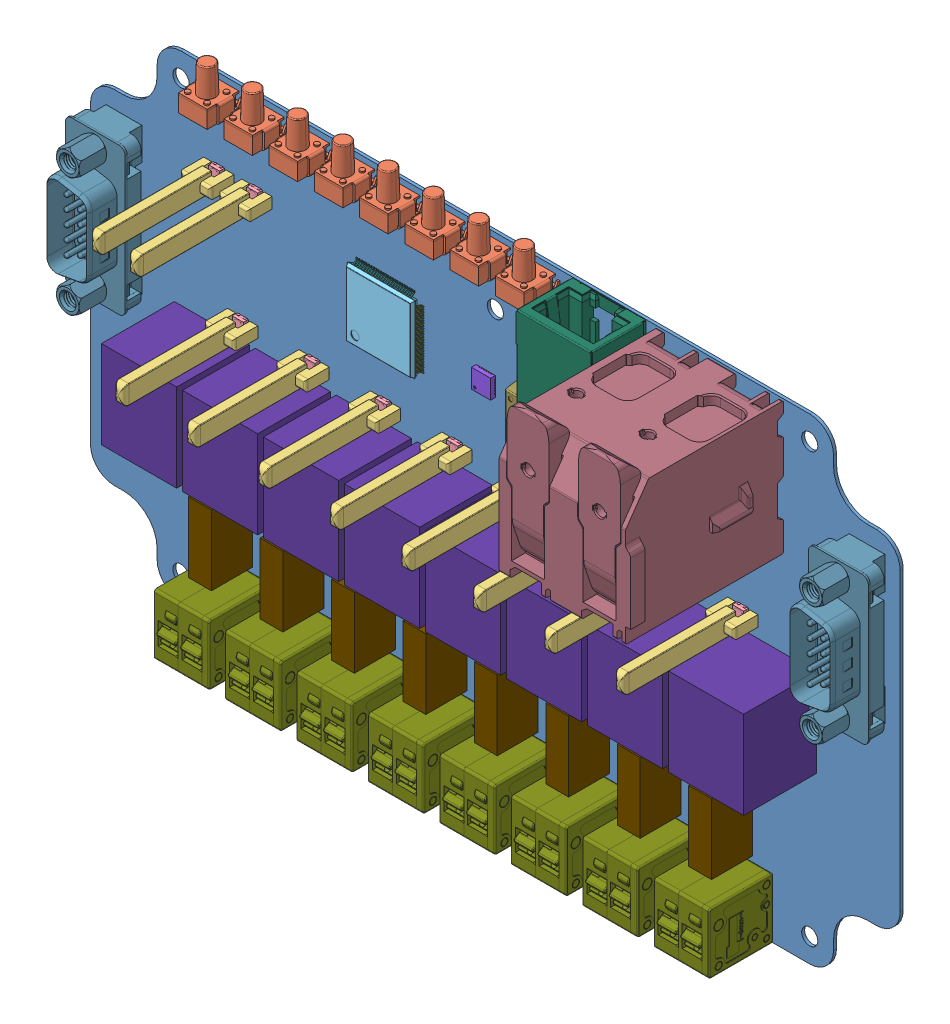
SolidWorks assembly KR-Df-01-EL-00 PCBA 2024_01_17, configuration Default. Lengths in mm.
Overall size (170 104.9 36.71).
192 component instances, 18 part files, 0 mates.
Components (placement in the parent):
- KR-Df-01-EL-00 PCBA 2024_01_17.step-1: KR-Df-01-EL-00 PCBA 2024_01_17.step [Default] at origin size (170 104.9 36.71)
  - Board.step-1: Board.step [Default] at origin size (170 100 0.62)
    - Open CASCADE STEP translator 7.5 1.1.1.step-1: Open CASCADE STEP translator 7.5 1.1.1.step [Default] at (0 0 -0.6237) size (170 100 0.62)
  - S607.step-1: S607.step [Default] at origin size (8.41 12.37 10.52)
    - 1-1825027-1.step-1: 1-1825027-1.step [Default] at (95 95.3 0) x (-1 0 0) z (0 1 0) size (8.41 10.52 12.37)
  - S606.step-1: S606.step [Default] at origin size (8.41 12.37 10.52)
    - 1-1825027-1.step-1: 1-1825027-1.step [Default] at (85.5 95.3 0) x (-1 0 0) z (0 1 0) size (8.41 10.52 12.37)
  - S605.step-1: S605.step [Default] at origin size (8.41 12.37 10.52)
    - 1-1825027-1.step-1: 1-1825027-1.step [Default] at (76 95.3 0) x (-1 0 0) z (0 1 0) size (8.41 10.52 12.37)
  - S604.step-1: S604.step [Default] at origin size (8.41 12.37 10.52)
    - 1-1825027-1.step-1: 1-1825027-1.step [Default] at (66.5 95.3 0) x (-1 0 0) z (0 1 0) size (8.41 10.52 12.37)
  - S603.step-1: S603.step [Default] at origin size (8.41 12.37 10.52)
    - 1-1825027-1.step-1: 1-1825027-1.step [Default] at (57 95.3 0) x (-1 0 0) z (0 1 0) size (8.41 10.52 12.37)
  - S602.step-1: S602.step [Default] at origin size (8.41 12.37 10.52)
    - 1-1825027-1.step-1: 1-1825027-1.step [Default] at (47.5 95.3 0) x (-1 0 0) z (0 1 0) size (8.41 10.52 12.37)
  - S601.step-1: S601.step [Default] at origin size (8.41 12.37 10.52)
    - 1-1825027-1.step-1: 1-1825027-1.step [Default] at (38 95.3 0) x (-1 0 0) z (0 1 0) size (8.41 10.52 12.37)
  - S600.step-1: S600.step [Default] at origin size (8.41 12.37 10.52)
    - 1-1825027-1.step-1: 1-1825027-1.step [Default] at (28.5 95.3 0) x (-1 0 0) z (0 1 0) size (8.41 10.52 12.37)
  - ME609.step-1: ME609.step [Default] at origin size (6.36 3.96 28.65)
    - BIVAR__INC_VLPR-24-1028-2_RGB8421504.step-1: BIVAR__INC_VLPR-24-1028-2_RGB8421504.step [Default] at (27 82 19.1) x (0 1 0) z (1 0 0) size (3.96 28.65 6.35)
  - ME608.step-1: ME608.step [Default] at origin size (6.36 3.96 28.65)
    - BIVAR__INC_VLPR-24-1028-2_RGB8421504.step-1: BIVAR__INC_VLPR-24-1028-2_RGB8421504.step [Default] at (35 82 19.1) x (0 1 0) z (1 0 0) size (3.96 28.65 6.35)
  - ME607.step-1: ME607.step [Default] at origin size (6.36 3.96 28.65)
    - BIVAR__INC_VLPR-24-1028-2_RGB8421504.step-1: BIVAR__INC_VLPR-24-1028-2_RGB8421504.step [Default] at (137 57 19.1) x (0 1 0) z (1 0 0) size (3.96 28.65 6.35)
  - ME606.step-1: ME606.step [Default] at origin size (6.36 3.96 28.65)
    - BIVAR__INC_VLPR-24-1028-2_RGB8421504.step-1: BIVAR__INC_VLPR-24-1028-2_RGB8421504.step [Default] at (122 57 19.1) x (0 1 0) z (1 0 0) size (3.96 28.65 6.35)
  - ME605.step-1: ME605.step [Default] at origin size (6.36 3.96 28.65)
    - BIVAR__INC_VLPR-24-1028-2_RGB8421504.step-1: BIVAR__INC_VLPR-24-1028-2_RGB8421504.step [Default] at (107 57 19.1) x (0 1 0) z (1 0 0) size (3.96 28.65 6.35)
  - ME604.step-1: ME604.step [Default] at origin size (6.36 3.96 28.65)
    - BIVAR__INC_VLPR-24-1028-2_RGB8421504.step-1: BIVAR__INC_VLPR-24-1028-2_RGB8421504.step [Default] at (92 57 19.1) x (0 1 0) z (1 0 0) size (3.96 28.65 6.35)
  - ME603.step-1: ME603.step [Default] at origin size (6.36 3.96 28.65)
    - BIVAR__INC_VLPR-24-1028-2_RGB8421504.step-1: BIVAR__INC_VLPR-24-1028-2_RGB8421504.step [Default] at (77 57 19.1) x (0 1 0) z (1 0 0) size (3.96 28.65 6.35)
  - ME602.step-1: ME602.step [Default] at origin size (6.36 3.96 28.65)
    - BIVAR__INC_VLPR-24-1028-2_RGB8421504.step-1: BIVAR__INC_VLPR-24-1028-2_RGB8421504.step [Default] at (62 57 19.1) x (0 1 0) z (1 0 0) size (3.96 28.65 6.35)
  - ME601.step-1: ME601.step [Default] at origin size (6.36 3.96 28.65)
    - BIVAR__INC_VLPR-24-1028-2_RGB8421504.step-1: BIVAR__INC_VLPR-24-1028-2_RGB8421504.step [Default] at (47 57 19.1) x (0 1 0) z (1 0 0) size (3.96 28.65 6.35)
  - ME600.step-1: ME600.step [Default] at origin size (6.36 3.96 28.65)
    - BIVAR__INC_VLPR-24-1028-2_RGB8421504.step-1: BIVAR__INC_VLPR-24-1028-2_RGB8421504.step [Default] at (32 57 19.1) x (0 1 0) z (1 0 0) size (3.96 28.65 6.35)
  - D609.step-1: D609.step [Default] at origin size (2.4 2.7 1.1)
    - IN-PI22TAT.step-1: IN-PI22TAT.step [Default] at (27 82 0) x (0 1 0) z (1 0 0) size (2.7 1.1 2.4)
  - D608.step-1: D608.step [Default] at origin size (2.4 2.7 1.1)
    - IN-PI22TAT.step-1: IN-PI22TAT.step [Default] at (35 82 0) x (0 1 0) z (1 0 0) size (2.7 1.1 2.4)
  - D607.step-1: D607.step [Default] at origin size (2.4 2.7 1.1)
    - IN-PI22TAT.step-1: IN-PI22TAT.step [Default] at (137 57 0) x (0 -1 0) z (-1 0 0) size (2.7 1.1 2.4)
  - D606.step-1: D606.step [Default] at origin size (2.4 2.7 1.1)
    - IN-PI22TAT.step-1: IN-PI22TAT.step [Default] at (122 57 0) x (0 -1 0) z (-1 0 0) size (2.7 1.1 2.4)
  - D605.step-1: D605.step [Default] at origin size (2.4 2.7 1.1)
    - IN-PI22TAT.step-1: IN-PI22TAT.step [Default] at (107 57 0) x (0 -1 0) z (-1 0 0) size (2.7 1.1 2.4)
  - D604.step-1: D604.step [Default] at origin size (2.4 2.7 1.1)
    - IN-PI22TAT.step-1: IN-PI22TAT.step [Default] at (92 57 0) x (0 -1 0) z (-1 0 0) size (2.7 1.1 2.4)
  - D603.step-1: D603.step [Default] at origin size (2.4 2.7 1.1)
    - IN-PI22TAT.step-1: IN-PI22TAT.step [Default] at (77 57 0) x (0 -1 0) z (-1 0 0) size (2.7 1.1 2.4)
  - D602.step-1: D602.step [Default] at origin size (2.4 2.7 1.1)
    - IN-PI22TAT.step-1: IN-PI22TAT.step [Default] at (62 57 0) x (0 -1 0) z (-1 0 0) size (2.7 1.1 2.4)
  - D601.step-1: D601.step [Default] at origin size (2.4 2.7 1.1)
    - IN-PI22TAT.step-1: IN-PI22TAT.step [Default] at (47 57 0) x (0 -1 0) z (-1 0 0) size (2.7 1.1 2.4)
  - D600.step-1: D600.step [Default] at origin size (2.4 2.7 1.1)
    - IN-PI22TAT.step-1: IN-PI22TAT.step [Default] at (32 57 0) x (0 -1 0) z (-1 0 0) size (2.7 1.1 2.4)
  - U500.step-1: U500.step [Default] at origin size (16 16 1.6)
    - STM32H573VIT6_RGB8421504.step-1: STM32H573VIT6_RGB8421504.step [Default] at (62 73 0) x (0 1 0) z (0 0 1) size (16 16 1.6)
      - Body.step-1: Body.step [Default] at origin size (14 14 1.5)
      - PinsArrayLR.step-1: PinsArrayLR.step [Default] at origin size (16 12.22 0.86)
      - PinsArrayTB.step-1: PinsArrayTB.step [Default] at origin size (12.22 16 0.86)
  - U200.step-1: U200.step [Default] at origin size (4 4 1)
    - 6014805872.step-1: 6014805872.step [Default] at (83 72 0) x (0 1 0) z (0 0 1) size (4 4 1)
      - Body-0.step-1: Body-0.step [Default] at (-2 -2 0) size (4 4 1)
        - Open CASCADE STEP translator 6.8 14.2.1.step-1: Open CASCADE STEP translator 6.8 14.2.1.step [Default] at origin size (4 4 1)
      - Pin_Shape.step-1: Pin_Shape.step [Default] at (-2 -1.37 0) size (0.4 0.24 0.2)
        - Open CASCADE STEP translator 6.8 14.4.1.step-1: Open CASCADE STEP translator 6.8 14.4.1.step [Default] at origin size (0.4 0.24 0.2)
      - Pin_Shape.step-2: Pin_Shape.step [Default] at (2 1.37 0) x (-1 0 0) z (0 0 1) size (0.4 0.24 0.2)
        - Open CASCADE STEP translator 6.8 14.4.1.step-1: Open CASCADE STEP translator 6.8 14.4.1.step [Default] at origin size (0.4 0.24 0.2)
      - Pin_Shape.step-3: Pin_Shape.step [Default] at (-2 -0.87 0) size (0.4 0.24 0.2)
        - Open CASCADE STEP translator 6.8 14.4.1.step-1: Open CASCADE STEP translator 6.8 14.4.1.step [Default] at origin size (0.4 0.24 0.2)
      - Pin_Shape.step-4: Pin_Shape.step [Default] at (2 0.87 0) x (-1 0 0) z (0 0 1) size (0.4 0.24 0.2)
        - Open CASCADE STEP translator 6.8 14.4.1.step-1: Open CASCADE STEP translator 6.8 14.4.1.step [Default] at origin size (0.4 0.24 0.2)
      - Pin_Shape.step-5: Pin_Shape.step [Default] at (-2 -0.37 0) size (0.4 0.24 0.2)
        - Open CASCADE STEP translator 6.8 14.4.1.step-1: Open CASCADE STEP translator 6.8 14.4.1.step [Default] at origin size (0.4 0.24 0.2)
      - Pin_Shape.step-6: Pin_Shape.step [Default] at (2 0.37 0) x (-1 0 0) z (0 0 1) size (0.4 0.24 0.2)
        - Open CASCADE STEP translator 6.8 14.4.1.step-1: Open CASCADE STEP translator 6.8 14.4.1.step [Default] at origin size (0.4 0.24 0.2)
      - Pin_Shape.step-7: Pin_Shape.step [Default] at (-2 0.13 0) size (0.4 0.24 0.2)
        - Open CASCADE STEP translator 6.8 14.4.1.step-1: Open CASCADE STEP translator 6.8 14.4.1.step [Default] at origin size (0.4 0.24 0.2)
      - Pin_Shape.step-8: Pin_Shape.step [Default] at (2 -0.13 0) x (-1 0 0) z (0 0 1) size (0.4 0.24 0.2)
        - Open CASCADE STEP translator 6.8 14.4.1.step-1: Open CASCADE STEP translator 6.8 14.4.1.step [Default] at origin size (0.4 0.24 0.2)
      - Pin_Shape.step-9: Pin_Shape.step [Default] at (-2 0.63 0) size (0.4 0.24 0.2)
        - Open CASCADE STEP translator 6.8 14.4.1.step-1: Open CASCADE STEP translator 6.8 14.4.1.step [Default] at origin size (0.4 0.24 0.2)
      - Pin_Shape.step-10: Pin_Shape.step [Default] at (2 -0.63 0) x (-1 0 0) z (0 0 1) size (0.4 0.24 0.2)
        - Open CASCADE STEP translator 6.8 14.4.1.step-1: Open CASCADE STEP translator 6.8 14.4.1.step [Default] at origin size (0.4 0.24 0.2)
      - Pin_Shape.step-11: Pin_Shape.step [Default] at (-2 1.13 0) size (0.4 0.24 0.2)
        - Open CASCADE STEP translator 6.8 14.4.1.step-1: Open CASCADE STEP translator 6.8 14.4.1.step [Default] at origin size (0.4 0.24 0.2)
      - Pin_Shape.step-12: Pin_Shape.step [Default] at (2 -1.13 0) x (-1 0 0) z (0 0 1) size (0.4 0.24 0.2)
        - Open CASCADE STEP translator 6.8 14.4.1.step-1: Open CASCADE STEP translator 6.8 14.4.1.step [Default] at origin size (0.4 0.24 0.2)
      - Pin_Shape.step-13: Pin_Shape.step [Default] at (-1.13 -2 0) x (0 1 0) z (0 0 1) size (0.4 0.24 0.2)
        - Open CASCADE STEP translator 6.8 14.4.1.step-1: Open CASCADE STEP translator 6.8 14.4.1.step [Default] at origin size (0.4 0.24 0.2)
      - Pin_Shape.step-14: Pin_Shape.step [Default] at (1.13 2 0) x (0 -1 0) z (0 0 1) size (0.4 0.24 0.2)
        - Open CASCADE STEP translator 6.8 14.4.1.step-1: Open CASCADE STEP translator 6.8 14.4.1.step [Default] at origin size (0.4 0.24 0.2)
      - Pin_Shape.step-15: Pin_Shape.step [Default] at (-0.63 -2 0) x (0 1 0) z (0 0 1) size (0.4 0.24 0.2)
        - Open CASCADE STEP translator 6.8 14.4.1.step-1: Open CASCADE STEP translator 6.8 14.4.1.step [Default] at origin size (0.4 0.24 0.2)
      - Pin_Shape.step-16: Pin_Shape.step [Default] at (0.63 2 0) x (0 -1 0) z (0 0 1) size (0.4 0.24 0.2)
        - Open CASCADE STEP translator 6.8 14.4.1.step-1: Open CASCADE STEP translator 6.8 14.4.1.step [Default] at origin size (0.4 0.24 0.2)
      - Pin_Shape.step-17: Pin_Shape.step [Default] at (-0.13 -2 0) x (0 1 0) z (0 0 1) size (0.4 0.24 0.2)
        - Open CASCADE STEP translator 6.8 14.4.1.step-1: Open CASCADE STEP translator 6.8 14.4.1.step [Default] at origin size (0.4 0.24 0.2)
      - Pin_Shape.step-18: Pin_Shape.step [Default] at (0.13 2 0) x (0 -1 0) z (0 0 1) size (0.4 0.24 0.2)
        - Open CASCADE STEP translator 6.8 14.4.1.step-1: Open CASCADE STEP translator 6.8 14.4.1.step [Default] at origin size (0.4 0.24 0.2)
      - Pin_Shape.step-19: Pin_Shape.step [Default] at (0.37 -2 0) x (0 1 0) z (0 0 1) size (0.4 0.24 0.2)
        - Open CASCADE STEP translator 6.8 14.4.1.step-1: Open CASCADE STEP translator 6.8 14.4.1.step [Default] at origin size (0.4 0.24 0.2)
      - Pin_Shape.step-20: Pin_Shape.step [Default] at (-0.37 2 0) x (0 -1 0) z (0 0 1) size (0.4 0.24 0.2)
        - Open CASCADE STEP translator 6.8 14.4.1.step-1: Open CASCADE STEP translator 6.8 14.4.1.step [Default] at origin size (0.4 0.24 0.2)
      - Pin_Shape.step-21: Pin_Shape.step [Default] at (0.87 -2 0) x (0 1 0) z (0 0 1) size (0.4 0.24 0.2)
        - Open CASCADE STEP translator 6.8 14.4.1.step-1: Open CASCADE STEP translator 6.8 14.4.1.step [Default] at origin size (0.4 0.24 0.2)
      - Pin_Shape.step-22: Pin_Shape.step [Default] at (-0.87 2 0) x (0 -1 0) z (0 0 1) size (0.4 0.24 0.2)
        - Open CASCADE STEP translator 6.8 14.4.1.step-1: Open CASCADE STEP translator 6.8 14.4.1.step [Default] at origin size (0.4 0.24 0.2)
      - Pin_Shape.step-23: Pin_Shape.step [Default] at (1.37 -2 0) x (0 1 0) z (0 0 1) size (0.4 0.24 0.2)
        - Open CASCADE STEP translator 6.8 14.4.1.step-1: Open CASCADE STEP translator 6.8 14.4.1.step [Default] at origin size (0.4 0.24 0.2)
      - Pin_Shape.step-24: Pin_Shape.step [Default] at (-1.37 2 0) x (0 -1 0) z (0 0 1) size (0.4 0.24 0.2)
        - Open CASCADE STEP translator 6.8 14.4.1.step-1: Open CASCADE STEP translator 6.8 14.4.1.step [Default] at origin size (0.4 0.24 0.2)
      - Open CASCADE STEP translator 6.8 14.1.step-1: Open CASCADE STEP translator 6.8 14.1.step [Default] at (-2 -2 0) size (0.51 0.51 0.01)
      - Thermal_Shape.step-1: Thermal_Shape.step [Default] at (-1.25 -1.25 -0.001) size (2.5 2.5 0)
  - T200.step-1: T200.step [Default] at origin size (9.3 12.8 5.68)
    - PT61018PEL.step-1: PT61018PEL.step [Default] at (99.35 78.3999 5.65) x (0 -1 0) z (1 0 0) size (12.8 5.68 9.3)
  - J400.step-1: J400.step [Default] at origin size (27.81 32.01 33.2)
    - 2616-1352.step-1: 2616-1352.step [Default] at (120.5 89.5 0) x (0 1 0) z (1 0 0) size (32.01 33.2 27.81)
  - J301.step-1: J301.step [Default] at origin size (12.55 30.81 15.4)
    - L717TSEH09POL2RM8--3DModel-STEP-533217.step-1: L717TSEH09POL2RM8--3DModel-STEP-533217.step [Default] at (169.275 51.58 0) x (0 1 0) z (1 0 0) size (30.81 15.4 12.55)
  - J300.step-1: J300.step [Default] at origin size (12.55 30.81 15.4)
    - L717TSEH09POL2RM8--3DModel-STEP-533217.step-1: L717TSEH09POL2RM8--3DModel-STEP-533217.step [Default] at (13.275 51.58 0) x (0 1 0) z (1 0 0) size (30.81 15.4 12.55)
  - P200.step-1: P200.step [Default] at origin size (16.33 18.55 13.95)
    - M-RJLSE-4X381-01T-REVT1.step-1: M-RJLSE-4X381-01T-REVT1.step [Default] at (108.9999 99.725 0) x (1 0 0) z (0 1 0) size (16.33 13.95 18.55)
  - P103.step-1: P103.step [Default] at origin size (11.62 12.71 17.41)
    - DGPS2.5R-5.0-02P-14-00Z(H).step-1: DGPS2.5R-5.0-02P-14-00Z(H).step [Default] at (76.8 0.1 0) x (1 0 0) z (0 -1 0) size (11.62 17.41 12.71)
  - P101.step-1: P101.step [Default] at origin size (11.62 12.71 17.41)
    - DGPS2.5R-5.0-02P-14-00Z(H).step-1: DGPS2.5R-5.0-02P-14-00Z(H).step [Default] at (46.8 0.1 0) x (1 0 0) z (0 -1 0) size (11.62 17.41 12.71)
  - P106.step-1: P106.step [Default] at origin size (11.62 12.71 17.41)
    - DGPS2.5R-5.0-02P-14-00Z(H).step-1: DGPS2.5R-5.0-02P-14-00Z(H).step [Default] at (121.8 0.1 0) x (1 0 0) z (0 -1 0) size (11.62 17.41 12.71)
  - P104.step-1: P104.step [Default] at origin size (11.62 12.71 17.41)
    - DGPS2.5R-5.0-02P-14-00Z(H).step-1: DGPS2.5R-5.0-02P-14-00Z(H).step [Default] at (91.8 0.1 0) x (1 0 0) z (0 -1 0) size (11.62 17.41 12.71)
  - P100.step-1: P100.step [Default] at origin size (11.62 12.71 17.41)
    - DGPS2.5R-5.0-02P-14-00Z(H).step-1: DGPS2.5R-5.0-02P-14-00Z(H).step [Default] at (31.8 0.1 0) x (1 0 0) z (0 -1 0) size (11.62 17.41 12.71)
  - P107.step-1: P107.step [Default] at origin size (11.62 12.71 17.41)
    - DGPS2.5R-5.0-02P-14-00Z(H).step-1: DGPS2.5R-5.0-02P-14-00Z(H).step [Default] at (136.8 0.1 0) x (1 0 0) z (0 -1 0) size (11.62 17.41 12.71)
  - P105.step-1: P105.step [Default] at origin size (11.62 12.71 17.41)
    - DGPS2.5R-5.0-02P-14-00Z(H).step-1: DGPS2.5R-5.0-02P-14-00Z(H).step [Default] at (106.8 0.1 0) x (1 0 0) z (0 -1 0) size (11.62 17.41 12.71)
  - P102.step-1: P102.step [Default] at origin size (11.62 12.71 17.41)
    - DGPS2.5R-5.0-02P-14-00Z(H).step-1: DGPS2.5R-5.0-02P-14-00Z(H).step [Default] at (61.8 0.1 0) x (1 0 0) z (0 -1 0) size (11.62 17.41 12.71)
  - K104.step-1: K104.step [Default] at origin size (15.8 18.4 15.29)
    - 6146511680.step-1: 6146511680.step [Default] at (93.5 44.55 0) size (15.8 18.4 15.29)
      - Extruded.step-1: Extruded.step [Default] at origin size (15.8 18.4 15.29)
  - K101.step-1: K101.step [Default] at origin size (15.8 18.4 15.29)
    - 6146511680.step-1: 6146511680.step [Default] at (42.5 44.55 0) size (15.8 18.4 15.29)
      - Extruded.step-1: Extruded.step [Default] at origin size (15.8 18.4 15.29)
  - K106.step-1: K106.step [Default] at origin size (15.8 18.4 15.29)
    - 6146511680.step-1: 6146511680.step [Default] at (127.5 44.55 0) size (15.8 18.4 15.29)
      - Extruded.step-1: Extruded.step [Default] at origin size (15.8 18.4 15.29)
  - K103.step-1: K103.step [Default] at origin size (15.8 18.4 15.29)
    - 6146511680.step-1: 6146511680.step [Default] at (76.5 44.55 0) size (15.8 18.4 15.29)
      - Extruded.step-1: Extruded.step [Default] at origin size (15.8 18.4 15.29)
  - K100.step-1: K100.step [Default] at origin size (15.8 18.4 15.29)
    - 6146511680.step-1: 6146511680.step [Default] at (25.5 44.55 0) size (15.8 18.4 15.29)
      - Extruded.step-1: Extruded.step [Default] at origin size (15.8 18.4 15.29)
  - K107.step-1: K107.step [Default] at origin size (15.8 18.4 15.29)
    - 6146511680.step-1: 6146511680.step [Default] at (144.5 44.55 0) size (15.8 18.4 15.29)
      - Extruded.step-1: Extruded.step [Default] at origin size (15.8 18.4 15.29)
  - K105.step-1: K105.step [Default] at origin size (15.8 18.4 15.29)
    - 6146511680.step-1: 6146511680.step [Default] at (110.5 44.55 0) size (15.8 18.4 15.29)
      - Extruded.step-1: Extruded.step [Default] at origin size (15.8 18.4 15.29)
  - K102.step-1: K102.step [Default] at origin size (15.8 18.4 15.29)
    - 6146511680.step-1: 6146511680.step [Default] at (59.5 44.55 0) size (15.8 18.4 15.29)
      - Extruded.step-1: Extruded.step [Default] at origin size (15.8 18.4 15.29)
  - F103.step-1: F103.step [Default] at origin size (4.8 14.7 8.6)
    - 6146509360.step-1: 6146509360.step [Default] at (76.6 21 0) size (4.8 14.7 8.6)
      - Extruded-1.step-1: Extruded-1.step [Default] at origin size (4.8 14.7 8.6)
  - F101.step-1: F101.step [Default] at origin size (4.8 14.7 8.6)
    - 6146509360.step-1: 6146509360.step [Default] at (46.6 21 0) size (4.8 14.7 8.6)
      - Extruded-1.step-1: Extruded-1.step [Default] at origin size (4.8 14.7 8.6)
  - F106.step-1: F106.step [Default] at origin size (4.8 14.7 8.6)
    - 6146509360.step-1: 6146509360.step [Default] at (121.6 21 0) size (4.8 14.7 8.6)
      - Extruded-1.step-1: Extruded-1.step [Default] at origin size (4.8 14.7 8.6)
  - F104.step-1: F104.step [Default] at origin size (4.8 14.7 8.6)
    - 6146509360.step-1: 6146509360.step [Default] at (91.6 21 0) size (4.8 14.7 8.6)
      - Extruded-1.step-1: Extruded-1.step [Default] at origin size (4.8 14.7 8.6)
  - F100.step-1: F100.step [Default] at origin size (4.8 14.7 8.6)
    - 6146509360.step-1: 6146509360.step [Default] at (31.6 21 0) size (4.8 14.7 8.6)
      - Extruded-1.step-1: Extruded-1.step [Default] at origin size (4.8 14.7 8.6)
  - F107.step-1: F107.step [Default] at origin size (4.8 14.7 8.6)
    - 6146509360.step-1: 6146509360.step [Default] at (136.6 21 0) size (4.8 14.7 8.6)
      - Extruded-1.step-1: Extruded-1.step [Default] at origin size (4.8 14.7 8.6)
  - F105.step-1: F105.step [Default] at origin size (4.8 14.7 8.6)
    - 6146509360.step-1: 6146509360.step [Default] at (106.6 21 0) size (4.8 14.7 8.6)
      - Extruded-1.step-1: Extruded-1.step [Default] at origin size (4.8 14.7 8.6)
  - F102.step-1: F102.step [Default] at origin size (4.8 14.7 8.6)
    - 6146509360.step-1: 6146509360.step [Default] at (61.6 21 0) size (4.8 14.7 8.6)
      - Extruded-1.step-1: Extruded-1.step [Default] at origin size (4.8 14.7 8.6)
